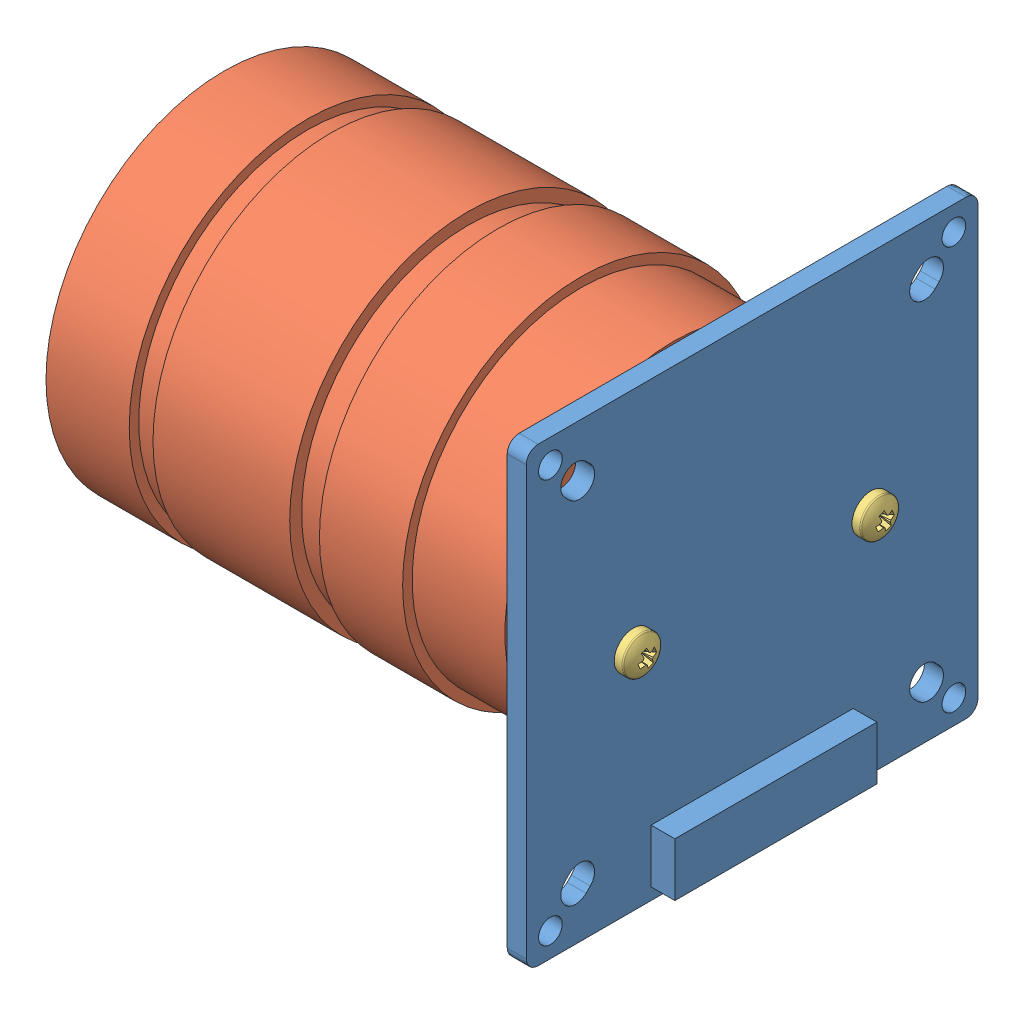
SolidWorks assembly IMX477 (12.3MP), configuration Initial. Lengths in mm.
Overall size (46.4 38 38).
4 component instances, 3 part files, 7 mates.
Components (placement in the parent):
- IMX477_ElectronicCard-1: IMX477_ElectronicCard [Initial] at origin size (3.6 38 38)
- IMX477_BasisCamera-1: IMX477_BasisCamera [Initial] x (-1 0 0) z (0 -1 0) size (42.8 30 30)
- ISO 7045 - M1.6 x 5 - Z - 5N-1: ISO 7045 - M1.6 x 5 - Z - 5N [ISO 7045 - M1.6 x 5 - Z - 5N] at (2.9 0 10) x (-1 0 0) z (0 0.924225 0.381849) size (6.27 3.2 3.2)
- ISO 7045 - M1.6 x 5 - Z - 5N-2: ISO 7045 - M1.6 x 5 - Z - 5N [ISO 7045 - M1.6 x 5 - Z - 5N] at (2.9 0 -10) x (-1 0 0) z (0 0.924225 0.381849) size (6.27 3.2 3.2)
Mates (geometry in assembly coordinates):
- Coïncidente1: coincident anti-aligned: plane of IMX477_ElectronicCard-1 through (0 0 0) normal (-1 0 0); plane of IMX477_BasisCamera-1 through (0 0 0) normal (1 0 0)
- Coaxiale1: concentric aligned: cylinder of IMX477_ElectronicCard-1 through (0 0 10) axis (1 0 0) radius 1; cylinder of IMX477_BasisCamera-1 through (-10.2498 0 10) axis (1 0 0) radius 1
- Coaxiale2: concentric aligned: cylinder of IMX477_ElectronicCard-1 through (0 0 -10) axis (1 0 0) radius 1; cylinder of IMX477_BasisCamera-1 through (-10.2498 0 -10) axis (1 0 0) radius 1
- Coaxiale31: concentric aligned: cylinder of IMX477_ElectronicCard-1 through (0 0 10) axis (1 0 0) radius 1; cylinder of ISO 7045 - M1.6 x 5 - Z - 5N-1 through (28.3 0 10) axis (1 0 0) radius 1.6
- Coïncidente21: coincident anti-aligned: plane of IMX477_ElectronicCard-1 through (1.6 0 0) normal (1 0 0); plane of ISO 7045 - M1.6 x 5 - Z - 5N-1 through (1.6 -0.3055 10.7394) normal (-1 0 0)
- Coaxiale41: concentric aligned: cylinder of IMX477_ElectronicCard-1 through (0 0 -10) axis (1 0 0) radius 1; cylinder of ISO 7045 - M1.6 x 5 - Z - 5N-2 through (28.3 0 -10) axis (1 0 0) radius 1.6
- Coïncidente31: coincident anti-aligned: plane of IMX477_ElectronicCard-1 through (1.6 0 0) normal (1 0 0); plane of ISO 7045 - M1.6 x 5 - Z - 5N-2 through (1.6 -0.3055 -9.2606) normal (-1 0 0)
